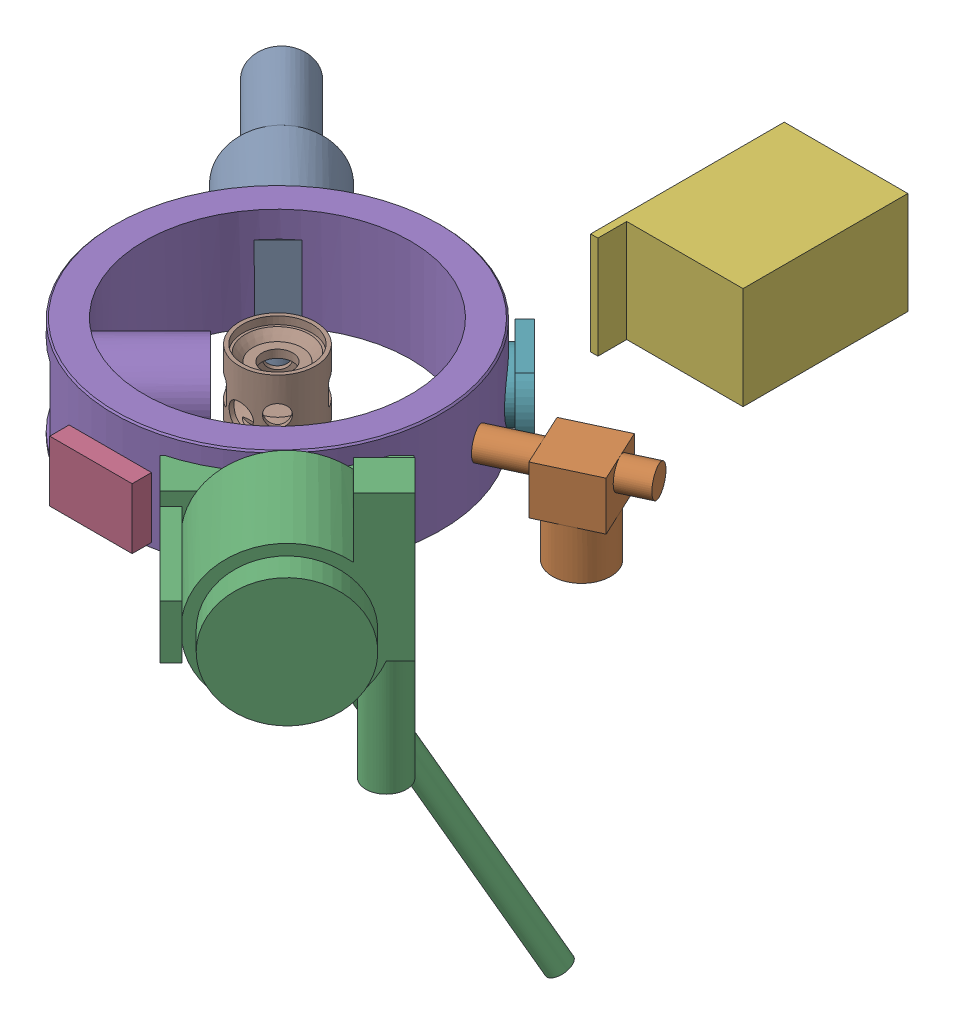
SolidWorks assembly JEOL 1200ex OL Module_SAP Polepiece column, configuration Default. Lengths in mm.
Overall size (440.74 300.19 466.71).
8 component instances, 7 part files, 0 mates.
Components (placement in the parent):
- goniometer_2-1: goniometer_2 [Default] at (-62.8669 -84.6886 -57.0048) x (-0.707107 0 0.707107) z (-0.707107 0 -0.707107) size (95.25 223.84 139.7)
- right_side_solenoid-1: right_side_solenoid [Default] at (147.1073 -100.5741 -43.6085) x (0.906308 0 -0.422618) z (0.422618 0 0.906308) size (88.9 63.5 38.1)
- goniometer-1: goniometer [Default] at (65.9959 -83.8823 68.2763) x (0.707107 0 -0.707107) z (0.707107 0 0.707107) size (191.82 300.19 120.65)
- aperture_objective-1: aperture_objective [Default] at (19.4443 -79.5187 108.9816) size (53.98 39.69 12.7)
  - aperture_objective_plate-1: aperture_objective_plate [Default] at (-21.021 -4.0137 7.4693) size (53.98 39.69 12.7)
- JEOL 1200EX OL Module Rev. B-1: JEOL 1200EX OL Module Rev. B [Default] at (-3.1347 -569.8886 5.4127) size (243.09 67 384.13)
- sap-1: sap [Default] at (-3.1347 -81.5386 5.4127) x (0.707107 0 0.707107) z (-0.707107 0 0.707107) size (50 49 50)
- Aperture blade-1: Aperture blade [Default] at (-3.1347 -88.6886 4.5934) x (0 0 1) z (-1 0 0) size (20 0.2 2)
